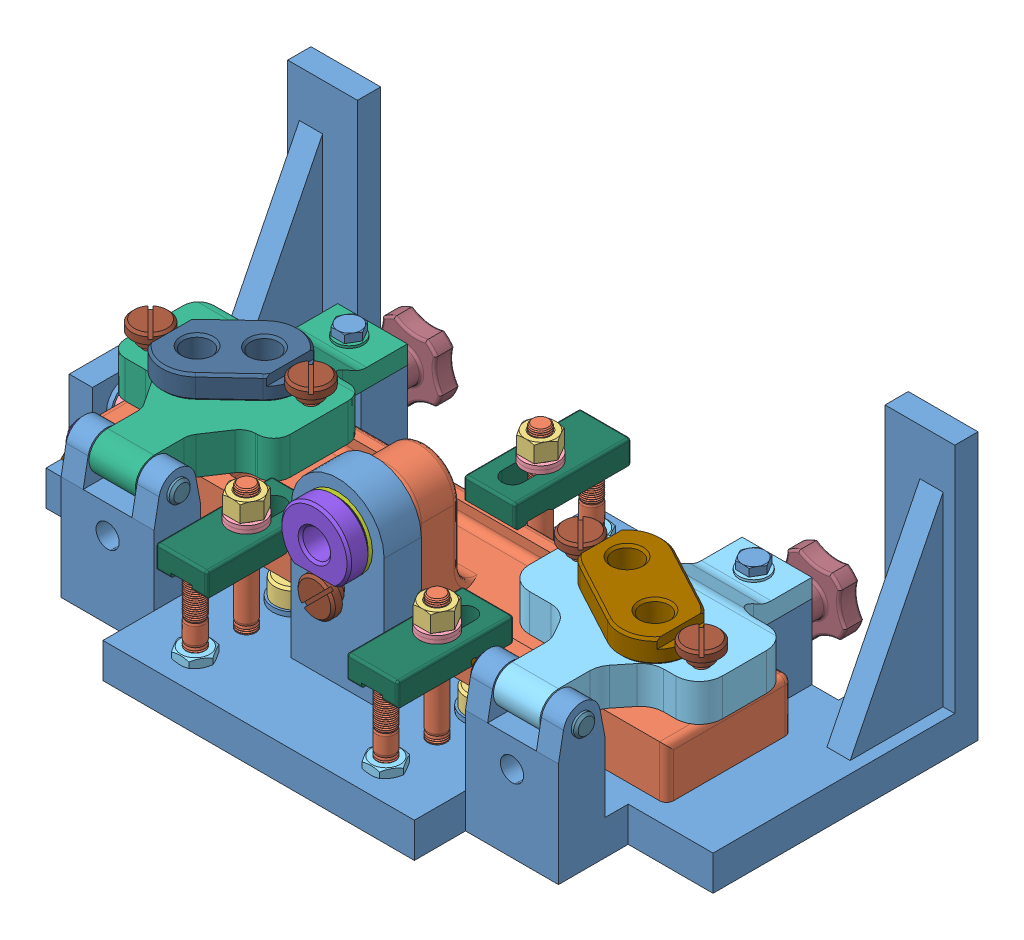
SolidWorks assembly 钻床夹具装配, configuration 默认. Lengths in mm.
Overall size (287 115 166).
59 component instances, 23 part files, 146 mates.
Components (placement in the parent):
- 钻床夹具（新1）-1: 钻床夹具（新1） [默认] at (194.1772 106.0566 199.8684) size (287 115 166)
- 前横架-1: 前横架 [默认] at (70.6772 129.0566 147.8684) x (1 0 0) z (0 1 0) size (247 54 64)
- A型支承钉-1: A型支承钉 [默认] at (194.1772 131.0566 96.8684) size (16 20 16)
- B型支承钉-1: B型支承钉 [默认] at (281.1772 139.0566 147.8684) x (1 0 0) z (0 1 0) size (16 20 16)
- A型支承钉-2: A型支承钉 [默认] at (235.1772 131.0566 143.8684) size (16 20 16)
- A型支承钉-3: A型支承钉 [默认] at (153.1772 131.0566 143.8684) size (16 20 16)
- B型支承钉-2: B型支承钉 [默认] at (107.1772 139.0566 147.8684) x (1 0 0) z (0 1 0) size (16 20 16)
- B型支承钉-3: B型支承钉 [默认] at (70.6772 139.0566 122.8684) x (0 0 1) z (0 1 0) size (16 20 16)
- 钻模板大-1: 钻模板大 [默认] at (292.6772 153.0566 127.8684) size (83 16 112)
- 钻模板小-1: 钻模板小 [默认] at (95.6772 153.0566 127.8684) size (71 16 112)
- 衬套-1: 衬套 [默认] at (194.1772 178.0566 149.8684) x (1 0 0) z (0 -1 0) size (30 16 30)
- 可换钻套-1: 可换钻套 [默认] at (194.1772 178.0566 149.8684) x (0 -1 0) z (-1 0 0) size (30 26 30)
- 特殊钻套1-1: 特殊钻套1 [默认] at (292.6772 153.0566 127.8684) x (1 0 0) z (0 1 0) size (56 44 26)
- 特殊钻套2-1: 特殊钻套2 [默认] at (110.6772 153.0566 113.8684) x (-1 0 0) z (0 1 0) size (45 44 26)
- 钻套螺钉M6×4-2: 钻套螺钉M6×4 [默认] at (194.1772 158.0566 157.8684) x (-0.707107 -0.707107 0) z (-0.707107 0.707107 0) size (16 18 16)
- 钻套螺钉M6×4-1: 钻套螺钉M6×4 [默认] at (130.6772 161.0566 113.8684) x (0.707107 0 0.707107) z (-0.707107 0 0.707107) size (16 18 16)
- 钻套螺钉M6×4-3: 钻套螺钉M6×4 [默认] at (75.6772 161.0566 127.8684) x (-0.707107 0 -0.707107) z (0.707107 0 -0.707107) size (16 18 16)
- 钻套螺钉M6×4-4: 钻套螺钉M6×4 [默认] at (246.6772 161.0566 113.8684) x (0.707107 0 0.707107) z (-0.707107 0 0.707107) size (16 18 16)
- 钻套螺钉M6×4-5: 钻套螺钉M6×4 [默认] at (312.6772 161.0566 127.8684) x (0.707107 0 0.707107) z (-0.707107 0 0.707107) size (16 18 16)
- AM6×50压紧螺钉-1: AM6×50压紧螺钉 [默认] at (281.1772 139.0566 43.8684) x (-0.707107 -0.707107 0) z (0 0 -1) size (6.06 6.06 49.99)
- AM6×50压紧螺钉-2: AM6×50压紧螺钉 [默认] at (107.1772 139.0566 43.8684) x (-0.707107 -0.707107 0) z (0 0 -1) size (6.06 6.06 49.99)
- BM6星形把手-1: BM6星形把手 [默认] at (281.1772 139.0566 41.8684) x (-0.707107 0.707107 0) z (0 0 -1) size (31.86 30.53 18.06)
- BM6星形把手-2: BM6星形把手 [默认] at (107.1772 139.0566 41.8684) x (-0.707107 0.707107 0) z (0 0 -1) size (31.86 30.53 18.06)
- 铰链轴-1: 铰链轴 [默认] at (256.1772 161.0566 167.8684) x (0 -0.707107 0.707107) z (-1 0 0) size (9 9 47)
- 铰链轴-2: 铰链轴 [默认] at (82.1772 161.0566 167.8684) x (0 0.707107 0.707107) z (-1 0 0) size (9 9 47)
- A8×50移动压板-1: A8×50移动压板 [默认] at (142.1772 151.0566 142.1184) x (0 0 1) z (-1 0 0) size (50 10 22)
- A8×50移动压板-2: A8×50移动压板 [默认] at (224.1772 151.0566 142.1184) x (0 0 1) z (-1 0 0) size (50 10 22)
- A8×50移动压板-3: A8×50移动压板 [默认] at (205.1772 151.0566 100.6184) x (0 0 -1) z (1 0 0) size (50 10 22)
- 辅助支撑螺柱_小-1: 辅助支撑螺柱_小 [默认] at (103.1772 101.7128 120.8684) size (8 20 8)
- 辅助支撑螺柱_小-2: 辅助支撑螺柱_小 [默认] at (279.6772 101.7128 120.8684) size (8 20 8)
- plain washers-n series-grade a gb-1: plain washers-n series-grade a gb [GB_FASTENER_WASHER_PWNA 6] at (85.3188 161.0566 167.8684) x (0 0 1) z (-1 0 0) size (12 12 1.6)
- plain washers-n series-grade a gb-2: plain washers-n series-grade a gb [GB_FASTENER_WASHER_PWNA 6] at (259.4007 161.0566 167.8684) x (0 0 1) z (-1 0 0) size (12 12 1.6)
- split pins-1: split pins [GB_CONNECTING_PIECE_PIN_AP 1.6X10] at (84.6772 165.4406 163.4843) x (0 -0.707107 0.707107) z (1 0 0) size (15.7 2.8 1.4)
- split pins-2: split pins [GB_CONNECTING_PIECE_PIN_AP 1.6X10] at (258.6772 165.4406 172.2525) x (0 -0.707107 -0.707107) z (1 0 0) size (15.7 2.8 1.4)
- hex head bolts-full thread grade c gb-7: hex head bolts-full thread grade c gb [GB_FASTENER_BOLT_HHBFTC M6X16-N] at (281.1772 166.0566 73.8686) x (0 -1 0) z (-0.866025 0 0.5) size (20 11.55 10)
- hex head bolts-full thread grade c gb-6: hex head bolts-full thread grade c gb [GB_FASTENER_BOLT_HHBFTC M6X16-N] at (107.1772 166.0566 73.8684) x (0 -1 0) z (0 0 -1) size (20 11.55 10)
- double end studs bm=2d gb-1: double end studs bm=2d gb [GB_FASTENER_BOLT_DESB20 A M8X25-S] at (235.1772 112.0566 186.1184) x (0 1 0) z (0 0 1) size (41 8 8)
- double end studs bm=2d gb-2: double end studs bm=2d gb [GB_FASTENER_BOLT_DESB20 A M8X50-S] at (235.1772 109.0566 164.1184) x (0 1 0) z (0 0 1) size (66 8 8)
- hex nut-fine pitch-style washer-grade ab gb-1: hex nut-fine pitch-style washer-grade ab gb [GB_HEXAGON_TYPE10_1 M8X1-S] at (235.1772 164.8566 164.1184) x (-1 0 0) z (0 -1 0) size (15.01 13 8.1)
- hex nut-fine pitch-style washer-grade ab gb-2: hex nut-fine pitch-style washer-grade ab gb [GB_HEXAGON_TYPE10_1 M8X1-S] at (153.1772 164.8566 164.1184) x (-1 0 0) z (0 -1 0) size (15.01 13 8.1)
- double end studs bm=2d gb-3: double end studs bm=2d gb [GB_FASTENER_BOLT_DESB20 A M8X50-S] at (153.1772 109.0566 164.1184) x (0 1 0) z (0.210743 0 0.977541) size (66 8 8)
- double end studs bm=2d gb-4: double end studs bm=2d gb [GB_FASTENER_BOLT_DESB20 A M8X50-S] at (194.1772 109.0566 78.6184) x (0 1 0) z (-0.024503 0 0.9997) size (66 8 8)
- hex nut-fine pitch-style washer-grade ab gb-3: hex nut-fine pitch-style washer-grade ab gb [GB_HEXAGON_TYPE10_1 M8X1-S] at (194.1772 164.8566 78.6184) x (-1 0 0) z (0 -1 0) size (15.01 13 8.1)
- double end studs bm=2d gb-5: double end studs bm=2d gb [GB_FASTENER_BOLT_DESB20 A M8X25-S] at (153.1772 112.0566 186.1184) x (0 1 0) z (0 0 1) size (41 8 8)
- double end studs bm=2d gb-6: double end studs bm=2d gb [GB_FASTENER_BOLT_DESB20 A M8X25-S] at (194.1772 112.0566 56.6184) x (0 1 0) z (0 0 1) size (41 8 8)
- plain washers-s series-grade a gb-1: plain washers-s series-grade a gb [GB_FASTENER_WASHER_PWSA 8] at (235.1772 162.6566 164.1184) x (-0.768939 0 -0.639322) z (0 1 0) size (15 15 1.6)
- plain washers-s series-grade a gb-2: plain washers-s series-grade a gb [GB_FASTENER_WASHER_PWSA 8] at (235.1772 162.6566 164.1184) x (-0.41646 0 0.909154) z (0 -1 0) size (15 15 1.6)
- plain washers-s series-grade a gb-3: plain washers-s series-grade a gb [GB_FASTENER_WASHER_PWSA 8] at (153.1772 161.0566 164.1184) x (1 0 0) z (0 -1 0) size (15 15 1.6)
- plain washers-s series-grade a gb-4: plain washers-s series-grade a gb [GB_FASTENER_WASHER_PWSA 8] at (153.1772 162.6566 164.1184) x (1 0 0) z (0 -1 0) size (15 15 1.6)
- plain washers-s series-grade a gb-5: plain washers-s series-grade a gb [GB_FASTENER_WASHER_PWSA 8] at (194.1772 164.2566 78.6184) x (1 0 0) z (0 1 0) size (15 15 1.6)
- plain washers-s series-grade a gb-6: plain washers-s series-grade a gb [GB_FASTENER_WASHER_PWSA 8] at (194.1772 162.6566 78.6184) x (1 0 0) z (0 1 0) size (15 15 1.6)
- plain washers-n series-grade a gb-3: plain washers-n series-grade a gb [GB_FASTENER_WASHER_PWNA 8] at (153.1772 151.0566 164.1184) x (1 0 0) z (0 1 0) size (16 16 1.6)
- plain washers-n series-grade a gb-4: plain washers-n series-grade a gb [GB_FASTENER_WASHER_PWNA 8] at (235.1772 151.0566 164.1184) x (1 0 0) z (0 1 0) size (16 16 1.6)
- plain washers-n series-grade a gb-5: plain washers-n series-grade a gb [GB_FASTENER_WASHER_PWNA 8] at (194.1772 151.0566 78.6184) x (1 0 0) z (0 1 0) size (16 16 1.6)
- hex thin nuts-grades ab-chamfered gb-1: hex thin nuts-grades ab-chamfered gb [GB_FASTENER_NUT_STNAB M8-N] at (153.1772 125.0566 186.1184) x (1 0 0) z (0 1 0) size (15.01 13 4)
- hex thin nuts-grades ab-chamfered gb-2: hex thin nuts-grades ab-chamfered gb [GB_FASTENER_NUT_STNAB M8-N] at (235.1772 125.0566 186.1184) x (1 0 0) z (0 1 0) size (15.01 13 4)
- hex thin nuts-grades ab-chamfered gb-3: hex thin nuts-grades ab-chamfered gb [GB_FASTENER_NUT_STNAB M8-N] at (194.1772 125.0566 56.6184) x (1 0 0) z (0 1 0) size (15.01 13 4)
- hex thin nuts-grades ab-chamfered gb-4: hex thin nuts-grades ab-chamfered gb [GB_FASTENER_NUT_STNAB M8-N] at (103.1772 125.0566 120.8684) x (1 0 0) z (0 1 0) size (15.01 13 4)
- hex thin nuts-grades ab-chamfered gb-5: hex thin nuts-grades ab-chamfered gb [GB_FASTENER_NUT_STNAB M8-N] at (279.6772 125.0566 120.8684) x (1 0 0) z (0 1 0) size (15.01 13 4)
Mates (geometry in assembly coordinates):
- 同心1: concentric: cylinder of assembly; cylinder of 钻床夹具（新1）-1 through (235.1772 108.0566 143.8684) axis (0 1 0) radius 5; cylinder of A型支承钉-2 through (235.1772 111.0566 143.8684) axis (0 -1 0) radius 5
- 重合1: coincident: plane of assembly; plane of 钻床夹具（新1）-1 through (235.1772 123.0566 143.8684) normal (0 1 0); plane of A型支承钉-2 through (243.1772 123.0566 143.8684) normal (0 -1 0)
- 同心2: concentric: cylinder of assembly; cylinder of 钻床夹具（新1）-1 through (153.1772 108.0566 143.8684) axis (0 1 0) radius 5; cylinder of A型支承钉-3 through (153.1772 111.0566 143.8684) axis (0 -1 0) radius 5
- 重合2: coincident: plane of assembly; plane of 钻床夹具（新1）-1 through (153.1772 123.0566 143.8684) normal (0 1 0); plane of A型支承钉-3 through (161.1772 123.0566 143.8684) normal (0 -1 0)
- 同心3: concentric: cylinder of assembly; cylinder of 钻床夹具（新1）-1 through (194.1772 108.0566 96.8684) axis (0 1 0) radius 5; cylinder of A型支承钉-1 through (194.1772 111.0566 96.8684) axis (0 -1 0) radius 5
- 重合3: coincident: plane of assembly; plane of 钻床夹具（新1）-1 through (194.1772 123.0566 96.8684) normal (0 1 0); plane of A型支承钉-1 through (202.1772 123.0566 96.8684) normal (0 -1 0)
- 同心4: concentric: cylinder of assembly; cylinder of 钻床夹具（新1）-1 through (107.1772 139.0566 199.8694) axis (0 0 -1) radius 5; cylinder of B型支承钉-2 through (107.1772 139.0566 167.8684) axis (0 0 1) radius 5
- 重合4: coincident: plane of assembly; plane of 钻床夹具（新1）-1 through (107.1772 139.0566 155.8684) normal (0 0 -1); plane of B型支承钉-2 through (115.1772 139.0566 155.8684) normal (0 0 1)
- 同心5: concentric: cylinder of assembly; cylinder of 钻床夹具（新1）-1 through (281.1772 139.0566 199.8694) axis (0 0 -1) radius 5; cylinder of B型支承钉-1 through (281.1772 139.0566 167.8684) axis (0 0 1) radius 5
- 重合5: coincident: plane of assembly; plane of 钻床夹具（新1）-1 through (281.1772 139.0566 155.8684) normal (0 0 -1); plane of B型支承钉-1 through (289.1772 139.0566 155.8684) normal (0 0 1)
- 同心6: concentric: cylinder of assembly; cylinder of 钻床夹具（新1）-1 through (50.6762 139.0566 122.8684) axis (1 0 0) radius 5; cylinder of B型支承钉-3 through (50.6772 139.0566 122.8684) axis (-1 0 0) radius 5
- 重合6: coincident: plane of assembly; plane of 钻床夹具（新1）-1 through (62.6772 139.0566 122.8684) normal (1 0 0); plane of B型支承钉-3 through (62.6772 139.0566 130.8684) normal (-1 0 0)
- 相切1: tangent anti-aligned: plane of 前横架-1 through (70.6772 151.0566 147.8684) normal (-1 0 0); sphere of B型支承钉-3
- 相切2: tangent anti-aligned: sphere of B型支承钉-1; plane of 前横架-1 through (70.6772 151.0566 147.8684) normal (0 0 1)
- 重合7: coincident anti-aligned: plane of A型支承钉-1 through (194.1772 131.0566 96.8684) normal (0 1 0); plane of 前横架-1 through (70.6772 131.0566 147.8684) normal (0 -1 0)
- 相切4: tangent anti-aligned: plane of 前横架-1 through (70.6772 151.0566 147.8684) normal (0 0 1); sphere of B型支承钉-2
- 同心7: concentric: cylinder of assembly; cylinder of 钻床夹具（新1）-1 through (269.6625 161.0566 167.8684) axis (-1 0 0) radius 3; cylinder of 钻模板小-1 through (67.6762 161.0566 167.8684) axis (1 0 0) radius 3
- 距离1: distance = 0.5 mm anti-aligned: plane of 钻模板小-1 through (117.1772 169.0566 152.8684) normal (1 0 0); plane of 钻床夹具（新1）-1 through (117.6772 198.0576 157.8684) normal (-1 0 0)
- 重合9: coincident: plane of assembly; plane of 钻床夹具（新1）-1 through (194.1772 153.0566 199.8684) normal (0 1 0); plane of 钻模板小-1 through (95.6772 153.0566 127.8684) normal (0 -1 0)
- 重合10: coincident: plane of assembly; plane of 钻床夹具（新1）-1 through (194.1772 153.0566 199.8684) normal (0 1 0); plane of 钻模板大-1 through (292.6772 153.0566 127.8684) normal (0 -1 0)
- 同心8: concentric: cylinder of assembly; cylinder of 钻床夹具（新1）-1 through (252.6919 161.0566 167.8684) axis (1 0 0) radius 3; cylinder of 钻模板大-1 through (271.1772 161.0566 167.8684) axis (1 0 0) radius 3
- 距离2: distance = 0.5 mm: plane of assembly; plane of 钻床夹具（新1）-1 through (270.6772 198.0576 157.8684) normal (1 0 0); plane of 钻模板大-1 through (271.1772 169.0566 150.8684) normal (-1 0 0)
- 同心9: concentric: cylinder of assembly; cylinder of 钻床夹具（新1）-1 through (194.1772 178.0566 43.8674) axis (0 0 1) radius 13; cylinder of 衬套-1 through (194.1772 178.0566 165.8684) axis (0 0 1) radius 13
- 重合12: coincident: plane of assembly; plane of 钻床夹具（新1）-1 through (194.1772 178.0566 162.8684) normal (0 0 1); plane of 衬套-1 through (206.1772 178.0566 162.8684) normal (0 0 -1)
- 同心10: concentric aligned: cylinder of 衬套-1 through (194.1772 178.0566 149.8684) axis (0 0 1) radius 9; cylinder of 可换钻套-1 through (194.1772 178.0566 175.8684) axis (0 0 1) radius 9
- 重合13: coincident anti-aligned: plane of 衬套-1 through (209.1772 178.0566 165.8684) normal (0 0 1); plane of 可换钻套-1 through (194.1772 178.0566 165.8684) normal (0 0 -1)
- 同心11: concentric: cylinder of assembly; cylinder of 钻床夹具（新1）-1 through (194.1772 158.0566 153.8684) axis (0 0 1) radius 3; cylinder of 钻套螺钉M6×4-2 through (194.1772 158.0566 175.8684) axis (0 0 1) radius 3
- 重合14: coincident anti-aligned: plane of 可换钻套-1 through (194.1772 178.0566 171.8684) normal (0 0 1); plane of 钻套螺钉M6×4-2 through (190.8184 154.6978 171.8684) normal (0 0 -1)
- 同心12: concentric aligned: cylinder of 钻模板大-1 through (266.6772 169.0566 113.8684) axis (0 -1 0) radius 9; cylinder of 特殊钻套1-1 through (266.6772 169.0566 113.8684) axis (0 -1 0) radius 9
- 同心13: concentric aligned: cylinder of 钻模板大-1 through (292.6772 169.0566 127.8684) axis (0 -1 0) radius 9; cylinder of 特殊钻套1-1 through (292.6772 169.0566 127.8684) axis (0 -1 0) radius 9
- 重合15: coincident anti-aligned: plane of 钻模板大-1 through (292.6772 169.0566 127.8684) normal (0 1 0); plane of 特殊钻套1-1 through (292.6772 169.0566 127.8684) normal (0 -1 0)
- 同心14: concentric aligned: cylinder of 钻模板小-1 through (110.6772 169.0566 113.8684) axis (0 -1 0) radius 9; cylinder of 特殊钻套2-1 through (110.6772 169.0566 113.8684) axis (0 -1 0) radius 9
- 同心15: concentric aligned: cylinder of 钻模板小-1 through (95.6772 169.0566 127.8684) axis (0 -1 0) radius 9; cylinder of 特殊钻套2-1 through (95.6772 169.0566 127.8684) axis (0 -1 0) radius 9
- 重合16: coincident anti-aligned: plane of 钻模板小-1 through (95.6772 169.0566 127.8684) normal (0 1 0); plane of 特殊钻套2-1 through (110.6772 169.0566 113.8684) normal (0 -1 0)
- 重合17: coincident anti-aligned: plane of 特殊钻套2-1 through (95.6772 175.0566 127.8684) normal (0 1 0); plane of 钻套螺钉M6×4-3 through (72.3184 175.0566 124.5096) normal (0 -1 0)
- 同心17: concentric anti-aligned: cylinder of 钻模板小-1 through (75.6772 169.0566 127.8684) axis (0 -1 0) radius 3; cylinder of 钻套螺钉M6×4-3 through (75.6772 179.0566 127.8684) axis (0 1 0) radius 3
- 重合18: coincident anti-aligned: plane of 特殊钻套2-1 through (110.6772 175.0566 113.8684) normal (0 1 0); plane of 钻套螺钉M6×4-1 through (134.0359 175.0566 117.2272) normal (0 -1 0)
- 重合19: coincident anti-aligned: plane of 特殊钻套1-1 through (266.6772 175.0566 113.8684) normal (0 1 0); plane of 钻套螺钉M6×4-4 through (250.0359 175.0566 117.2272) normal (0 -1 0)
- 重合20: coincident anti-aligned: plane of 钻套螺钉M6×4-5 through (316.0359 175.0566 131.2272) normal (0 -1 0); plane of 特殊钻套1-1 through (292.6772 175.0566 127.8684) normal (0 1 0)
- 同心18: concentric anti-aligned: cylinder of 钻模板大-1 through (312.6772 169.0566 127.8684) axis (0 -1 0) radius 3; cylinder of 钻套螺钉M6×4-5 through (312.6772 179.0566 127.8684) axis (0 1 0) radius 3
- 同心19: concentric anti-aligned: cylinder of 钻模板大-1 through (246.6772 169.0566 113.8684) axis (0 -1 0) radius 3; cylinder of 钻套螺钉M6×4-4 through (246.6772 179.0566 113.8684) axis (0 1 0) radius 3
- 同心20: concentric anti-aligned: cylinder of 钻模板小-1 through (130.6772 169.0566 113.8684) axis (0 -1 0) radius 3; cylinder of 钻套螺钉M6×4-1 through (130.6772 179.0566 113.8684) axis (0 1 0) radius 3
- 相切6: tangent anti-aligned: plane of 前横架-1 through (70.6772 151.0566 93.8684) normal (0 0 -1); sphere of AM6×50压紧螺钉-1
- 同心21: concentric: cylinder of assembly; cylinder of 钻床夹具（新1）-1 through (281.1772 139.0566 83.8684) axis (0 0 -1) radius 3; cylinder of AM6×50压紧螺钉-1 through (281.1772 139.0566 43.8684) axis (0 0 -1) radius 2.25
- 同心22: concentric: cylinder of assembly; cylinder of 钻床夹具（新1）-1 through (107.1772 139.0566 83.8684) axis (0 0 -1) radius 3; cylinder of AM6×50压紧螺钉-2 through (107.1772 139.0566 43.8684) axis (0 0 -1) radius 2.25
- 相切7: tangent anti-aligned: plane of 前横架-1 through (70.6772 151.0566 93.8684) normal (0 0 -1); sphere of AM6×50压紧螺钉-2
- 同心23: concentric aligned: cylinder of AM6×50压紧螺钉-2 through (107.1772 139.0566 43.8684) axis (0 0 -1) radius 2.25; cylinder of BM6星形把手-2 through (107.1772 139.0566 41.8684) axis (0 0 -1) radius 7
- 同心24: concentric anti-aligned: cylinder of AM6×50压紧螺钉-2 through (109.2985 141.1779 54.8684) axis (-0.707107 -0.707107 0) radius 1; cylinder of BM6星形把手-2 through (96.9396 128.819 54.8684) axis (0.707107 0.707107 0) radius 1
- 同心25: concentric anti-aligned: cylinder of AM6×50压紧螺钉-1 through (283.2985 141.1779 54.8684) axis (-0.707107 -0.707107 0) radius 1; cylinder of BM6星形把手-1 through (270.9396 128.819 54.8684) axis (0.707107 0.707107 0) radius 1
- 同心26: concentric aligned: cylinder of AM6×50压紧螺钉-1 through (281.1772 139.0566 43.8684) axis (0 0 -1) radius 2.25; cylinder of BM6星形把手-1 through (281.1772 139.0566 41.8684) axis (0 0 -1) radius 7
- 同心27: concentric: cylinder of assembly; cylinder of 钻床夹具（新1）-1 through (252.6919 161.0566 167.8684) axis (1 0 0) radius 3; cylinder of 铰链轴-1 through (303.1772 161.0566 167.8684) axis (1 0 0) radius 3
- 重合21: coincident: plane of 钻床夹具（新1）-1 through (301.1772 121.0566 147.8684) normal (1 0 0); plane of 铰链轴-1 through (301.1772 162.4708 166.4542) normal (-1 0 0)
- 同心28: concentric: cylinder of assembly; cylinder of ?; cylinder of 钻床夹具（新1）-1 through (269.6625 161.0566 167.8684) axis (-1 0 0) radius 3; cylinder of 铰链轴-2 through (129.1772 161.0566 167.8684) axis (1 0 0) radius 3; cylinder of ?; cylinder of ?
- 重合22: coincident: plane of 钻床夹具（新1）-1 through (127.1772 151.0566 177.8684) normal (1 0 0); plane of 铰链轴-2 through (127.1772 159.6423 166.4542) normal (-1 0 0)
- 同心29: concentric anti-aligned: cylinder of 铰链轴-2 through (84.6772 157.8746 171.0504) axis (0 0.707107 -0.707107) radius 0.7; cylinder of split pins-1 through (84.6772 163.1779 165.7471) axis (0 -0.707107 0.707107) radius 0.7
- 同心30: concentric anti-aligned: cylinder of 铰链轴-2 through (129.1772 161.0566 167.8684) axis (1 0 0) radius 3; cylinder of plain washers-n series-grade a gb-1 through (86.9188 161.0566 167.8684) axis (-1 0 0) radius 3.2
- 同心31: concentric anti-aligned: cylinder of 铰链轴-1 through (258.6772 157.8746 164.6864) axis (0 0.707107 0.707107) radius 0.7; cylinder of split pins-2 through (258.6772 163.1779 169.9897) axis (0 -0.707107 -0.707107) radius 0.7
- 同心32: concentric anti-aligned: cylinder of 铰链轴-1 through (303.1772 161.0566 167.8684) axis (1 0 0) radius 3; cylinder of plain washers-n series-grade a gb-2 through (261.0007 161.0566 167.8684) axis (-1 0 0) radius 3.2
- 相切8: tangent: curve of 铰链轴-1; circle of split pins-2
- 相切9: tangent: circle of 铰链轴-2; circle of split pins-1
- 垂直1: perpendicular: plane of plain washers-n series-grade a gb-1 through (85.3188 161.0566 167.8684) normal (-1 0 0); plane of split pins-1 through (83.9772 163.1779 165.7471) normal (0 -0.707107 -0.707107)
- 垂直2: perpendicular: plane of plain washers-n series-grade a gb-2 through (259.4007 161.0566 167.8684) normal (-1 0 0); plane of split pins-2 through (257.9772 163.1779 169.9897) normal (0 0.707107 -0.707107)
- 角度1: planar angle = 2.356194 rad aligned: plane of split pins-1 through (83.9772 163.1779 165.7471) normal (0 -0.707107 -0.707107); plane of 钻床夹具（新1）-1 through (87.1772 121.0566 177.8684) normal (0 0 1)
- 角度2: planar angle = 0.785398 rad: plane of 钻床夹具（新1）-1 through (301.1772 121.0566 177.8684) normal (0 0 1); plane of split pins-2 through (257.9772 163.1779 169.9897) normal (0 0.707107 -0.707107)
- 重合32: coincident aligned: circle of 钻模板大-1; cylinder of hex head bolts-full thread grade c gb-7 through (281.1772 146.0566 73.8686) axis (0 1 0) radius 3
- 重合33: coincident anti-aligned: plane of 钻模板大-1 through (281.1772 162.0566 73.8686) normal (0 1 0); plane of hex head bolts-full thread grade c gb-7 through (275.4037 162.0566 73.8686) normal (0 -1 0)
- 同心38: concentric aligned: cylinder of 钻模板小-1 through (107.1772 153.0566 73.8684) axis (0 1 0) radius 3; cylinder of hex head bolts-full thread grade c gb-6 through (107.1772 146.0566 73.8684) axis (0 1 0) radius 3
- 重合34: coincident anti-aligned: plane of 钻模板小-1 through (107.1772 162.0566 73.8684) normal (0 1 0); plane of hex head bolts-full thread grade c gb-6 through (110.0639 162.0566 68.8684) normal (0 -1 0)
- 同心39: concentric: cylinder of assembly; cylinder of 钻床夹具（新1）-1 through (153.1772 106.0566 164.1184) axis (0 1 0) radius 4; cylinder of A8×50移动压板-1 through (153.1772 161.0566 164.1184) axis (0 -1 0) radius 4.5
- 重合35: coincident anti-aligned: plane of 前横架-1 through (70.6772 151.0566 147.8684) normal (0 1 0); plane of A8×50移动压板-2 through (224.1772 151.0566 142.1184) normal (0 -1 0)
- 同心41: concentric: cylinder of 钻床夹具（新1）-1 through (235.1772 106.0566 164.1184) axis (0 1 0) radius 4; cylinder of A8×50移动压板-2 through (235.1772 161.0566 164.1184) axis (0 -1 0) radius 4.5
- 重合36: coincident anti-aligned: plane of 前横架-1 through (70.6772 151.0566 147.8684) normal (0 1 0); plane of A8×50移动压板-1 through (142.1772 151.0566 142.1184) normal (0 -1 0)
- 重合37: coincident anti-aligned: plane of 前横架-1 through (70.6772 151.0566 147.8684) normal (0 1 0); plane of A8×50移动压板-3 through (205.1772 151.0566 100.6184) normal (0 -1 0)
- 同心43: concentric: cylinder of 钻床夹具（新1）-1 through (194.1772 106.0566 78.6184) axis (0 1 0) radius 4; cylinder of A8×50移动压板-3 through (194.1772 161.0566 78.6184) axis (0 -1 0) radius 4.5
- 平行1: parallel aligned: plane of 前横架-1 through (70.6772 151.0566 93.8684) normal (0 0 -1); plane of A8×50移动压板-3 through (205.1772 161.0566 50.6184) normal (0 0 -1)
- 同心44: concentric: cylinder of assembly; cylinder of 钻床夹具（新1）-1 through (235.1772 106.0566 164.1184) axis (0 1 0) radius 4; cylinder of double end studs bm=2d gb-2 through (235.1772 107.7457 164.1184) axis (0 -1 0) radius 4
- 同心45: concentric: cylinder of assembly; cylinder of 钻床夹具（新1）-1 through (235.1772 106.0566 186.1184) axis (0 1 0) radius 4; cylinder of double end studs bm=2d gb-1 through (235.1772 110.7457 186.1184) axis (0 -1 0) radius 4
- 重合38: coincident anti-aligned: plane of A8×50移动压板-2 through (235.1772 153.0566 152.1184) normal (0 -1 0); plane of double end studs bm=2d gb-1 through (231.1772 153.0566 186.1184) normal (0 1 0)
- 同心46: concentric: cylinder of double end studs bm=2d gb-2 through (235.1772 107.7457 164.1184) axis (0 -1 0) radius 4; cylinder of hex nut-fine pitch-style washer-grade ab gb-1 through (235.1772 172.3566 164.1184) axis (0 -1 0) radius 3.4585
- 同心47: concentric: cylinder of assembly; cylinder of 钻床夹具（新1）-1 through (153.1772 106.0566 164.1184) axis (0 1 0) radius 4; cylinder of double end studs bm=2d gb-3 through (153.1772 107.7457 164.1184) axis (0 -1 0) radius 4
- 同心48: concentric: cylinder of hex nut-fine pitch-style washer-grade ab gb-2 through (153.1772 172.3566 164.1184) axis (0 -1 0) radius 3.4585; cylinder of double end studs bm=2d gb-3 through (153.1772 107.7457 164.1184) axis (0 -1 0) radius 4
- 同心49: concentric: cylinder of assembly; cylinder of 钻床夹具（新1）-1 through (194.1772 106.0566 78.6184) axis (0 1 0) radius 4; cylinder of double end studs bm=2d gb-4 through (194.1772 107.7457 78.6184) axis (0 -1 0) radius 4
- 同心50: concentric: cylinder of double end studs bm=2d gb-4 through (194.1772 107.7457 78.6184) axis (0 -1 0) radius 4; cylinder of hex nut-fine pitch-style washer-grade ab gb-3 through (194.1772 172.3566 78.6184) axis (0 -1 0) radius 3.4585
- 同心51: concentric: cylinder of assembly; cylinder of 钻床夹具（新1）-1 through (153.1772 106.0566 186.1184) axis (0 1 0) radius 4; cylinder of double end studs bm=2d gb-5 through (153.1772 110.7457 186.1184) axis (0 -1 0) radius 4
- 重合39: coincident anti-aligned: plane of A8×50移动压板-1 through (153.1772 153.0566 152.1184) normal (0 -1 0); plane of double end studs bm=2d gb-5 through (149.1772 153.0566 186.1184) normal (0 1 0)
- 同心52: concentric: cylinder of assembly; cylinder of 钻床夹具（新1）-1 through (194.1772 106.0566 56.6184) axis (0 1 0) radius 4; cylinder of double end studs bm=2d gb-6 through (194.1772 110.7457 56.6184) axis (0 -1 0) radius 4
- 重合40: coincident anti-aligned: plane of A8×50移动压板-3 through (194.1772 153.0566 90.6184) normal (0 -1 0); plane of double end studs bm=2d gb-6 through (190.1772 153.0566 56.6184) normal (0 1 0)
- 距离3: distance = 12 mm: plane of assembly; plane of 钻床夹具（新1）-1 through (194.1772 121.0566 199.8684) normal (0 1 0); plane of double end studs bm=2d gb-4 through (194.1772 109.0566 78.6184) normal (0 -1 0)
- 距离4: distance = 12 mm: plane of assembly; plane of 钻床夹具（新1）-1 through (194.1772 121.0566 199.8684) normal (0 1 0); plane of double end studs bm=2d gb-2 through (235.1772 109.0566 164.1184) normal (0 -1 0)
- 距离5: distance = 12 mm: plane of assembly; plane of 钻床夹具（新1）-1 through (194.1772 121.0566 199.8684) normal (0 1 0); plane of double end studs bm=2d gb-3 through (153.1772 109.0566 164.1184) normal (0 -1 0)
- 重合44: coincident anti-aligned: plane of A8×50移动压板-1 through (142.1772 161.0566 142.1184) normal (0 1 0); plane of plain washers-s series-grade a gb-3 through (153.1772 161.0566 164.1184) normal (0 -1 0)
- 同心53: concentric anti-aligned: cone of double end studs bm=2d gb-3 through (153.1772 166.7356 164.1184) axis (0 1 0); cylinder of plain washers-s series-grade a gb-3 through (153.1772 162.6566 164.1184) axis (0 -1 0) radius 4.2
- 重合45: coincident anti-aligned: plane of plain washers-s series-grade a gb-3 through (153.1772 162.6566 164.1184) normal (0 1 0); plane of plain washers-s series-grade a gb-4 through (153.1772 162.6566 164.1184) normal (0 -1 0)
- 同心54: concentric anti-aligned: cone of double end studs bm=2d gb-3 through (153.1772 169.171 164.1184) axis (0 1 0); cylinder of plain washers-s series-grade a gb-4 through (153.1772 164.2566 164.1184) axis (0 -1 0) radius 4.2
- 同心55: concentric anti-aligned: circle of double end studs bm=2d gb-2; cylinder of plain washers-s series-grade a gb-1 through (235.1772 161.0566 164.1184) axis (0 1 0) radius 4.2
- 同心56: concentric aligned: circle of double end studs bm=2d gb-2; cylinder of plain washers-s series-grade a gb-2 through (235.1772 164.2566 164.1184) axis (0 -1 0) radius 4.2
- 重合49: coincident anti-aligned: plane of A8×50移动压板-2 through (224.1772 161.0566 142.1184) normal (0 1 0); plane of plain washers-s series-grade a gb-1 through (235.1772 161.0566 164.1184) normal (0 -1 0)
- 重合50: coincident anti-aligned: plane of plain washers-s series-grade a gb-1 through (235.1772 162.6566 164.1184) normal (0 1 0); plane of plain washers-s series-grade a gb-2 through (235.1772 162.6566 164.1184) normal (0 -1 0)
- 重合51: coincident anti-aligned: plane of hex nut-fine pitch-style washer-grade ab gb-1 through (235.1772 164.2566 164.1184) normal (0 -1 0); plane of plain washers-s series-grade a gb-2 through (235.1772 164.2566 164.1184) normal (0 1 0)
- 同心57: concentric anti-aligned: circle of double end studs bm=2d gb-4; cylinder of plain washers-s series-grade a gb-5 through (194.1772 162.6566 78.6184) axis (0 1 0) radius 4.2
- 同心58: concentric anti-aligned: circle of double end studs bm=2d gb-4; cylinder of plain washers-s series-grade a gb-6 through (194.1772 161.0566 78.6184) axis (0 1 0) radius 4.2
- 重合52: coincident anti-aligned: plane of plain washers-s series-grade a gb-5 through (194.1772 162.6566 78.6184) normal (0 -1 0); plane of plain washers-s series-grade a gb-6 through (194.1772 162.6566 78.6184) normal (0 1 0)
- 重合53: coincident anti-aligned: plane of A8×50移动压板-3 through (205.1772 161.0566 100.6184) normal (0 1 0); plane of plain washers-s series-grade a gb-6 through (194.1772 161.0566 78.6184) normal (0 -1 0)
- 重合54: coincident anti-aligned: plane of hex nut-fine pitch-style washer-grade ab gb-3 through (194.1772 164.2566 78.6184) normal (0 -1 0); plane of plain washers-s series-grade a gb-5 through (194.1772 164.2566 78.6184) normal (0 1 0)
- 同心59: concentric anti-aligned: cylinder of double end studs bm=2d gb-3 through (153.1772 107.7457 164.1184) axis (0 -1 0) radius 4; cylinder of plain washers-n series-grade a gb-3 through (153.1772 149.4566 164.1184) axis (0 1 0) radius 4.2
- 同心60: concentric anti-aligned: cylinder of double end studs bm=2d gb-2 through (235.1772 107.7457 164.1184) axis (0 -1 0) radius 4; cylinder of plain washers-n series-grade a gb-4 through (235.1772 149.4566 164.1184) axis (0 1 0) radius 4.2
- 同心61: concentric anti-aligned: cylinder of double end studs bm=2d gb-4 through (194.1772 107.7457 78.6184) axis (0 -1 0) radius 4; cylinder of plain washers-n series-grade a gb-5 through (194.1772 149.4566 78.6184) axis (0 1 0) radius 4.2
- 重合55: coincident anti-aligned: plane of A8×50移动压板-1 through (142.1772 151.0566 142.1184) normal (0 -1 0); plane of plain washers-n series-grade a gb-3 through (153.1772 151.0566 164.1184) normal (0 1 0)
- 重合56: coincident anti-aligned: plane of A8×50移动压板-2 through (224.1772 151.0566 142.1184) normal (0 -1 0); plane of plain washers-n series-grade a gb-4 through (235.1772 151.0566 164.1184) normal (0 1 0)
- 重合57: coincident anti-aligned: plane of A8×50移动压板-3 through (205.1772 151.0566 100.6184) normal (0 -1 0); plane of plain washers-n series-grade a gb-5 through (194.1772 151.0566 78.6184) normal (0 1 0)
- 同心62: concentric anti-aligned: cylinder of hex thin nuts-grades ab-chamfered gb-1 through (153.1772 121.0566 186.1184) axis (0 1 0) radius 3.3235; cylinder of double end studs bm=2d gb-5 through (153.1772 110.7457 186.1184) axis (0 -1 0) radius 4
- 同心63: concentric anti-aligned: cylinder of hex thin nuts-grades ab-chamfered gb-2 through (235.1772 121.0566 186.1184) axis (0 1 0) radius 3.3235; cylinder of double end studs bm=2d gb-1 through (235.1772 110.7457 186.1184) axis (0 -1 0) radius 4
- 同心64: concentric anti-aligned: cylinder of double end studs bm=2d gb-6 through (194.1772 110.7457 56.6184) axis (0 -1 0) radius 4; cylinder of hex thin nuts-grades ab-chamfered gb-3 through (194.1772 121.0566 56.6184) axis (0 1 0) radius 3.3235
- 重合58: coincident: plane of 钻床夹具（新1）-1 through (194.1772 121.0566 199.8684) normal (0 1 0); plane of hex thin nuts-grades ab-chamfered gb-1 through (156.9299 121.0566 192.6184) normal (0 -1 0)
- 重合59: coincident: plane of 钻床夹具（新1）-1 through (194.1772 121.0566 199.8684) normal (0 1 0); plane of hex thin nuts-grades ab-chamfered gb-2 through (238.9299 121.0566 192.6184) normal (0 -1 0)
- 重合60: coincident: plane of 钻床夹具（新1）-1 through (194.1772 121.0566 199.8684) normal (0 1 0); plane of hex thin nuts-grades ab-chamfered gb-3 through (197.9299 121.0566 63.1184) normal (0 -1 0)
- 相切10: tangent anti-aligned: plane of 前横架-1 through (70.6772 129.0566 147.8684) normal (0 -1 0); sphere of 辅助支撑螺柱_小-1
- 相切11: tangent anti-aligned: plane of 前横架-1 through (70.6772 129.0566 147.8684) normal (0 -1 0); sphere of 辅助支撑螺柱_小-2
- 同心65: concentric anti-aligned: cylinder of 辅助支撑螺柱_小-1 through (103.1772 109.0566 120.8684) axis (0 -1 0) radius 4; circle of hex thin nuts-grades ab-chamfered gb-4
- 同心66: concentric anti-aligned: cylinder of 辅助支撑螺柱_小-2 through (279.6772 109.0566 120.8684) axis (0 -1 0) radius 4; cylinder of hex thin nuts-grades ab-chamfered gb-5 through (279.6772 121.0566 120.8684) axis (0 1 0) radius 3.3235
- 重合61: coincident: plane of 钻床夹具（新1）-1 through (194.1772 121.0566 199.8684) normal (0 1 0); plane of hex thin nuts-grades ab-chamfered gb-5 through (283.4299 121.0566 127.3684) normal (0 -1 0)
- 同心67: concentric: cylinder of 钻床夹具（新1）-1 through (279.6772 106.0566 120.8684) axis (0 1 0) radius 4; cylinder of 辅助支撑螺柱_小-2 through (279.6772 109.0566 120.8684) axis (0 -1 0) radius 4
- 重合62: coincident: plane of 钻床夹具（新1）-1 through (194.1772 121.0566 199.8684) normal (0 1 0); plane of hex thin nuts-grades ab-chamfered gb-4 through (106.9299 121.0566 127.3684) normal (0 -1 0)
- 同心68: concentric: cylinder of 钻床夹具（新1）-1 through (103.1772 106.0566 120.8684) axis (0 1 0) radius 4; cylinder of 辅助支撑螺柱_小-1 through (103.1772 109.0566 120.8684) axis (0 -1 0) radius 4
- 平行2: parallel aligned: plane of A8×50移动压板-2 through (224.1772 161.0566 192.1184) normal (0 0 1); plane of hex nut-fine pitch-style washer-grade ab gb-1 through (238.9299 172.3566 170.6184) normal (0 0 1)
- 平行3: parallel aligned: plane of A8×50移动压板-1 through (142.1772 161.0566 192.1184) normal (0 0 1); plane of hex nut-fine pitch-style washer-grade ab gb-2 through (156.9299 172.3566 170.6184) normal (0 0 1)
- 重合65: coincident anti-aligned: plane of hex nut-fine pitch-style washer-grade ab gb-2 through (153.1772 164.2566 164.1184) normal (0 -1 0); plane of plain washers-s series-grade a gb-4 through (153.1772 164.2566 164.1184) normal (0 1 0)
- 平行4: parallel: plane of 钻床夹具（新1）-1 through (87.1772 121.0566 177.8684) normal (0 0 1); plane of A8×50移动压板-1 through (142.1772 161.0566 192.1184) normal (0 0 1)
- 平行5: parallel: plane of 钻床夹具（新1）-1 through (301.1772 121.0566 177.8684) normal (0 0 1); plane of A8×50移动压板-2 through (224.1772 161.0566 192.1184) normal (0 0 1)
- 平行6: parallel: plane of 钻床夹具（新1）-1 through (182.1772 121.0566 43.8684) normal (0 0 -1); plane of A8×50移动压板-3 through (205.1772 161.0566 50.6184) normal (0 0 -1)
- 平行7: parallel aligned: plane of A8×50移动压板-3 through (205.1772 161.0566 50.6184) normal (0 0 -1); plane of hex nut-fine pitch-style washer-grade ab gb-3 through (190.4244 172.3566 72.1184) normal (0 0 -1)
- 平行8: parallel: plane of 钻床夹具（新1）-1 through (127.1772 121.0566 199.8684) normal (0 0 1); plane of hex thin nuts-grades ab-chamfered gb-1 through (149.4244 121.0566 192.6184) normal (0 0 1)
- 平行9: parallel: plane of 钻床夹具（新1）-1 through (127.1772 121.0566 199.8684) normal (0 0 1); plane of hex thin nuts-grades ab-chamfered gb-2 through (231.4244 121.0566 192.6184) normal (0 0 1)
- 平行10: parallel aligned: plane of 钻模板小-1 through (92.1772 169.0566 63.8684) normal (0 0 -1); plane of hex head bolts-full thread grade c gb-6 through (104.2904 162.0566 68.8684) normal (0 0 -1)
- 平行11: parallel aligned: plane of 钻模板大-1 through (266.1772 169.0566 63.8686) normal (0 0 -1); plane of hex head bolts-full thread grade c gb-7 through (278.2904 162.0566 68.8686) normal (0 0 -1)
- 平行12: parallel: plane of 钻床夹具（新1）-1 through (182.1772 121.0566 43.8684) normal (0 0 -1); plane of hex thin nuts-grades ab-chamfered gb-3 through (197.9299 121.0566 50.1184) normal (0 0 -1)
- 平行13: parallel: plane of 钻床夹具（新1）-1 through (301.1772 121.0566 177.8684) normal (0 0 1); plane of hex thin nuts-grades ab-chamfered gb-5 through (275.9244 121.0566 127.3684) normal (0 0 1)
- 平行14: parallel: plane of 钻床夹具（新1）-1 through (87.1772 121.0566 177.8684) normal (0 0 1); plane of hex thin nuts-grades ab-chamfered gb-4 through (99.4244 121.0566 127.3684) normal (0 0 1)
- 角度8: planar angle = 0.785398 rad: plane of assembly; plane of 钻床夹具（新1）-1 through (194.1772 121.0566 199.8684) normal (0 1 0); plane of AM6×50压紧螺钉-1 through (279.3576 136.6713 45.8684) normal (-0.707107 0.707107 0)
- 角度9: planar angle = 0.785398 rad: plane of assembly; plane of 钻床夹具（新1）-1 through (194.1772 121.0566 199.8684) normal (0 1 0); plane of AM6×50压紧螺钉-2 through (105.3576 136.6713 45.8684) normal (-0.707107 0.707107 0)
- 平行21: parallel: plane of assembly; plane of 钻床夹具（新1）-1 through (194.1772 121.0566 199.8684) normal (0 1 0); plane of 可换钻套-1 through (204.3752 167.0566 171.8684) normal (0 -1 0)
- 角度3: planar angle = 0.785398 rad aligned: plane of 钻套螺钉M6×4-2 through (200.3394 163.1582 173.8684) normal (-0.707107 0.707107 0); plane of 钻床夹具（新1）-1 through (194.1772 121.0566 199.8684) normal (0 1 0)
- 角度4: planar angle = 2.356194 rad: plane of assembly; plane of 钻床夹具（新1）-1 through (65.6772 163.5566 116.8684) normal (1 0 0); plane of 钻套螺钉M6×4-3 through (80.7788 177.0566 134.0307) normal (0.707107 0 -0.707107)
- 角度5: planar angle = 2.356194 rad aligned: plane of 钻套螺钉M6×4-1 through (125.5756 177.0566 107.7061) normal (-0.707107 0 0.707107); plane of 钻床夹具（新1）-1 through (65.6772 163.5566 116.8684) normal (1 0 0)
- 角度6: planar angle = 2.356194 rad aligned: plane of 钻套螺钉M6×4-4 through (241.5756 177.0566 107.7061) normal (-0.707107 0 0.707107); plane of 钻模板大-1 through (291.1772 169.0566 167.8684) normal (1 0 0)
- 角度7: planar angle = 0.785398 rad anti-aligned: plane of 钻套螺钉M6×4-5 through (307.5756 177.0566 121.7061) normal (-0.707107 0 0.707107); plane of 钻模板大-1 through (321.6772 169.0566 98.8686) normal (1 0 0)
